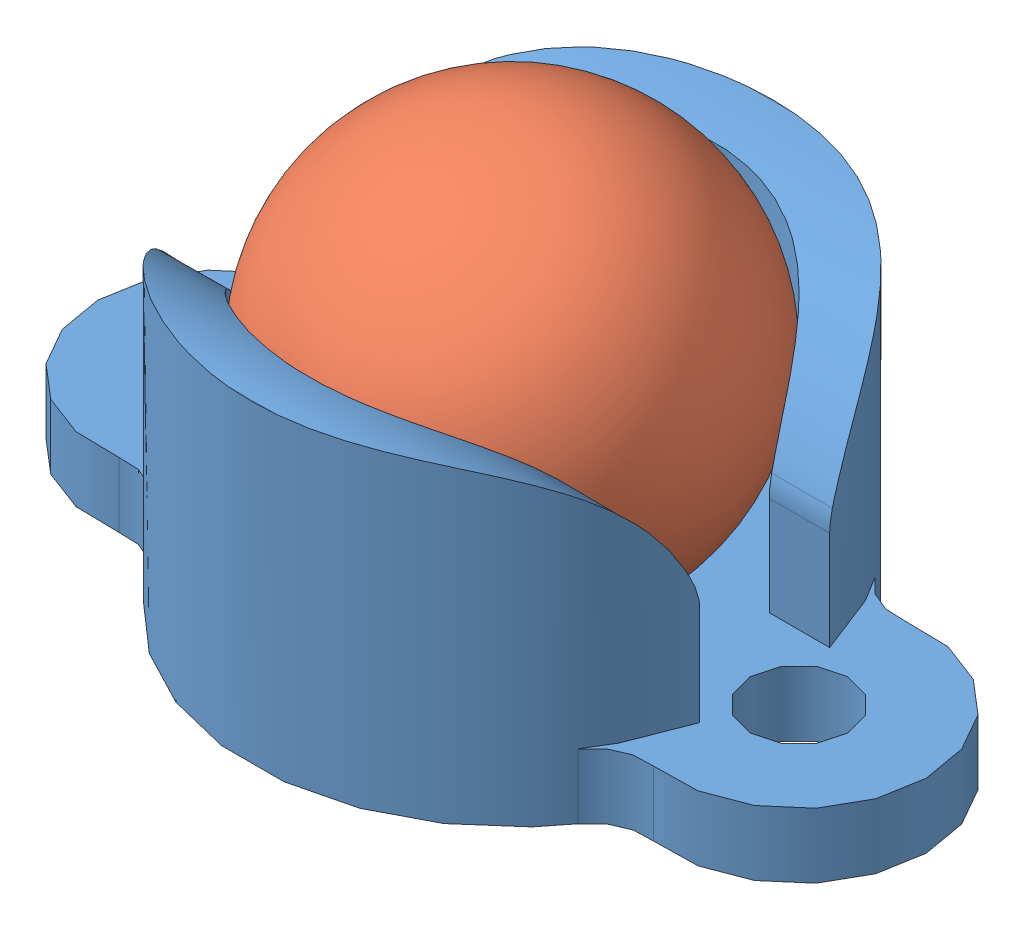
SolidWorks assembly rsw-pololu-caster-1239(0.375d), configuration Default. Lengths in mm.
Overall size (19.43 15.16 12.4).
2 component instances, 2 part files, 1 mates.
Components (placement in the parent):
- rsw-caster-housing-1239(0.375d)-1: rsw-caster-housing-1239(0.375d) [Default] at (0.0078 -2.0462 1.386) size (19.43 7.39 12.24)
- rsw-caster-ball-1239(0.375d)-1: rsw-caster-ball-1239(0.375d) [Default] at (0.0078 3.3513 1.386) x (0.57264 0.75924 0.309254) z (-0.22209 -0.219452 0.950009) size (9.53 9.53 9.53)
Mates (geometry in assembly coordinates):
- Distance5: distance = 0.635 mm aligned: plane of rsw-caster-housing-1239(0.375d)-1 through (0.0078 -2.0462 1.386) normal (0 -1 0); sphere of rsw-caster-ball-1239(0.375d)-1
